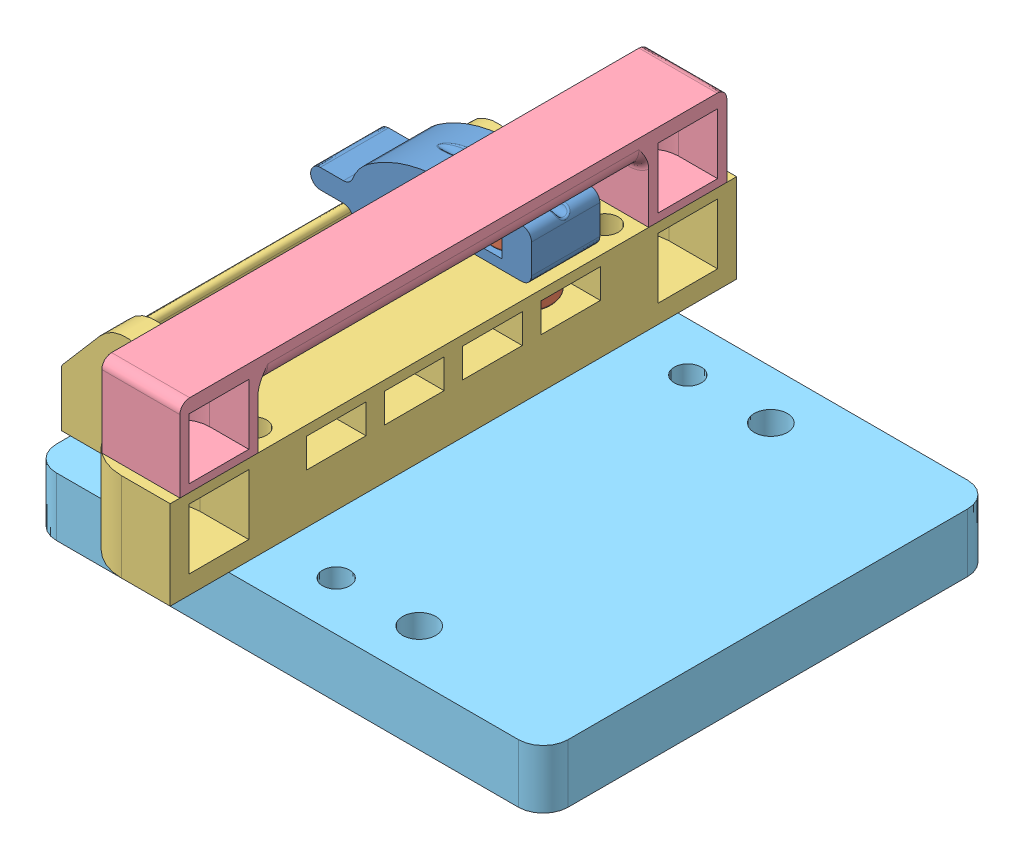
SolidWorks assembly fingers, configuration Default. Lengths in mm.
Overall size (55.32 23.49 58).
7 component instances, 5 part files, 6 mates.
Components (placement in the parent):
- Finger With Magnet-1: Finger With Magnet [Default] x (0 0 1) z (-1 0 0) size (7.5 10.88 22.62)
  - finger-1: finger [Default] x (0 0 -1) z (-1 0 0) size (22.62 10.88 7.5)
  - magnet-1: magnet [Default] at (0 3.6875 -9.525) x (0 0 1) z (-1 0 0) size (6 3 6)
- Part4^fingers-1: Part4^fingers [Default] at origin size (21.12 11.6 58) (virtual)
- magnet-2: magnet [Default] at (9.525 -1.5125 0) size (6 3 6)
- Part5^fingers-1: Part5^fingers [Default] at origin size (8 8.4 56) (virtual)
- Part6^fingers-1: Part6^fingers [Default] at origin size (52.4 6 46) (virtual)
Mates (geometry in assembly coordinates):
- Coincident1: coincident anti-aligned: line of Finger With Magnet-1 through (0 0 88.99) axis (0 0 -1)
- Coincident2: coincident aligned: plane of Finger With Magnet-1 through (0 0 0) normal (0 0 1)
- Coincident3: coincident aligned: plane of Finger With Magnet-1 through (0 0 0) normal (0 1 0)
- Concentric2: concentric aligned: cylinder of Finger With Magnet-1/magnet-1 through (9.525 5.1875 0) axis (0 -1 0) radius 3; cylinder of magnet-2 through (9.525 -0.0125 0) axis (0 -1 0) radius 3
- Distance2: distance = 1.2 mm anti-aligned: plane of magnet-2 through (9.525 -0.0125 0) normal (0 1 0); plane of Finger With Magnet-1/finger-1 through (14.025 1.1875 -3.5) normal (0 -1 0)
- Parallel1: parallel aligned: plane of magnet-2 through (9.525 -1.5125 0) normal (1 0 0)
